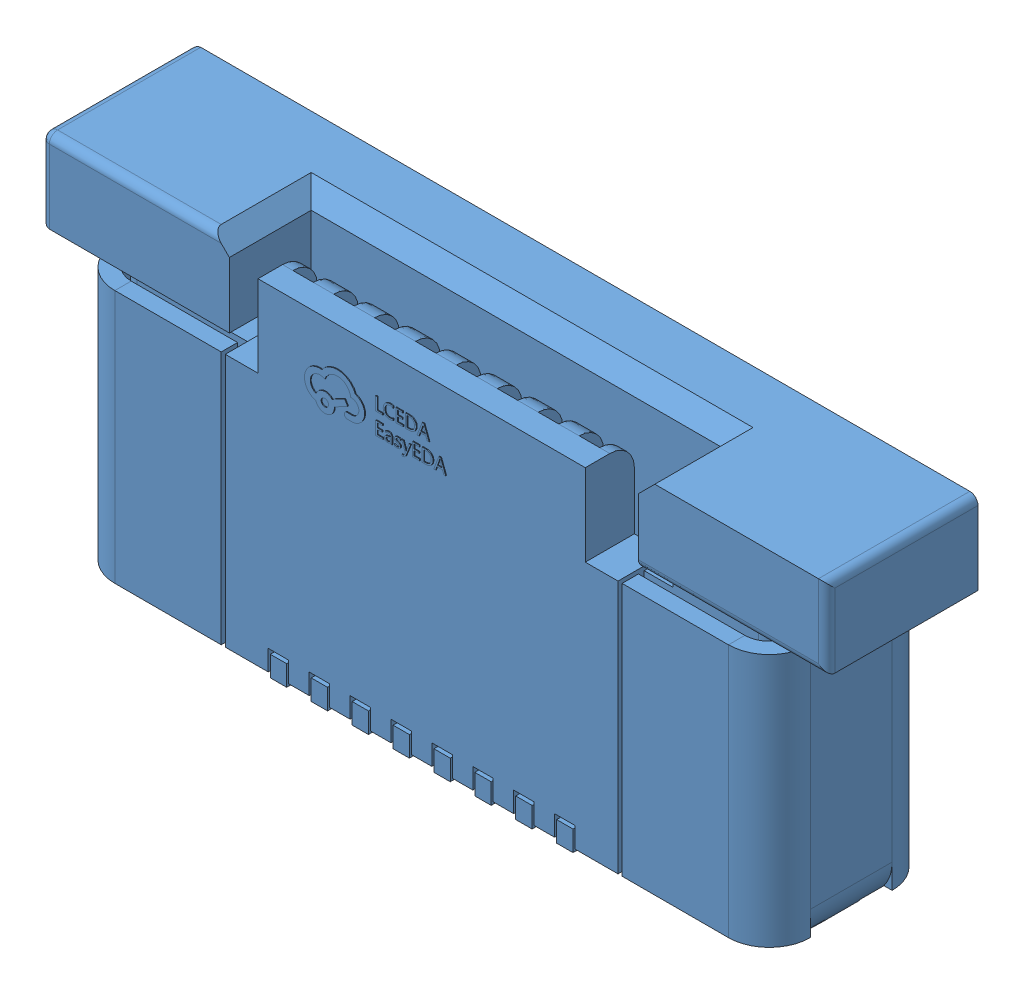
SolidWorks assembly FPC-SMD-8P-型号1, configuration 默认. Lengths in mm.
Overall size (9.6 5.2 2.01).
4 component instances, 1 part files, 0 mates.
Components (placement in the parent):
- FPC-SMD-8P-型号1(2)^FPC-SMD-8P-型号1-1: FPC-SMD-8P-型号1(2)^FPC-SMD-8P-型号1 [默认] at origin size (9.6 5.2 2.01) (virtual)
  - FPC1^FPC-SMD-8P-型号1(2)_FPC-SMD-8P-型号1-1: FPC1^FPC-SMD-8P-型号1(2)_FPC-SMD-8P-型号1 [默认] at (0.127 -8.763 1.6001) size (9.6 5.2 2.01) (virtual)
    - FPC-SMD_P0.5-8P_LCS-SH-H2.0^FPC1_FPC-SMD-8P-型号1(2)_FPC-SMD-8P-型号1-1: FPC-SMD_P0.5-8P_LCS-SH-H2.0^FPC1_FPC-SMD-8P-型号1(2)_FPC-SMD-8P-型号1 [默认] at origin size (9.6 5.2 2.01) (virtual)
      - COMPOUND^FPC-SMD_P0.5-8P_LCS-SH-H2.0_FPC1_FPC-SMD-8P-型号1(2)_FPC-SMD-8P-型号1-1: COMPOUND^FPC-SMD_P0.5-8P_LCS-SH-H2.0_FPC1_FPC-SMD-8P-型号1(2)_FPC-SMD-8P-型号1 [默认] at origin size (9.6 5.2 2.01) (virtual)
